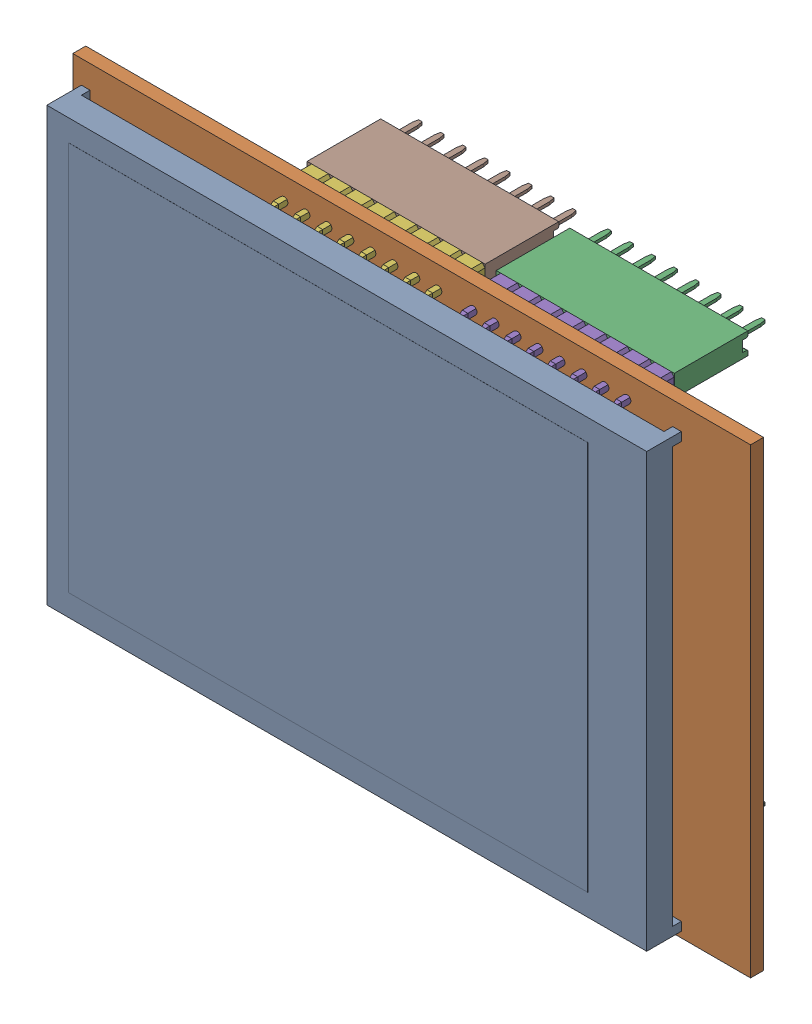
SolidWorks assembly U1, configuration Default. Lengths in mm.
Overall size (78.3 53.34 20.75).
10 component instances, 5 part files, 0 mates.
Components (placement in the parent):
- LCDassembly-1: LCDassembly [Default] at (43.644 27.5 -0.96) x (-1 0 0) z (0 0 1) size (78.3 53.34 20.75)
  - baseboard-1: baseboard [Default] at (-5.088 0 11.04) x (-1 0 0) z (0 0 1) size (78.3 53.34 6.51)
  - HEADER8-1: HEADER8 [Default] at (-16.01 -24.1265 0) x (-1 0 0) z (0 1 0) size (20.57 11.7 2.5)
  - SIL6-1: SIL6 [Default] at (-18.55 24.13 11.04) x (-1 0 0) z (0 1 0) size (15.24 11.2 2.5)
  - SIL8-1: SIL8 [Default] at (-16.01 -24.13 11.04) x (-1 0 0) z (0 1 0) size (20.32 11.2 2.5)
  - SIL8-2: SIL8 [Default] at (5.834 -24.13 11.04) x (-1 0 0) z (0 1 0) size (20.32 11.2 2.5)
  - SIL6-2: SIL6 [Default] at (-0.77 24.13 11.04) x (-1 0 0) z (0 1 0) size (15.24 11.2 2.5)
  - HEADER8-2: HEADER8 [Default] at (5.834 -24.1265 0) x (-1 0 0) z (0 1 0) size (20.57 11.7 2.5)
  - HEADER6-1: HEADER6 [Default] at (-18.55 24.1335 0) x (-1 0 0) z (0 1 0) size (15.49 11.7 2.5)
  - HEADER6-2: HEADER6 [Default] at (-0.77 24.1335 0) x (-1 0 0) z (0 1 0) size (15.49 11.7 2.5)
